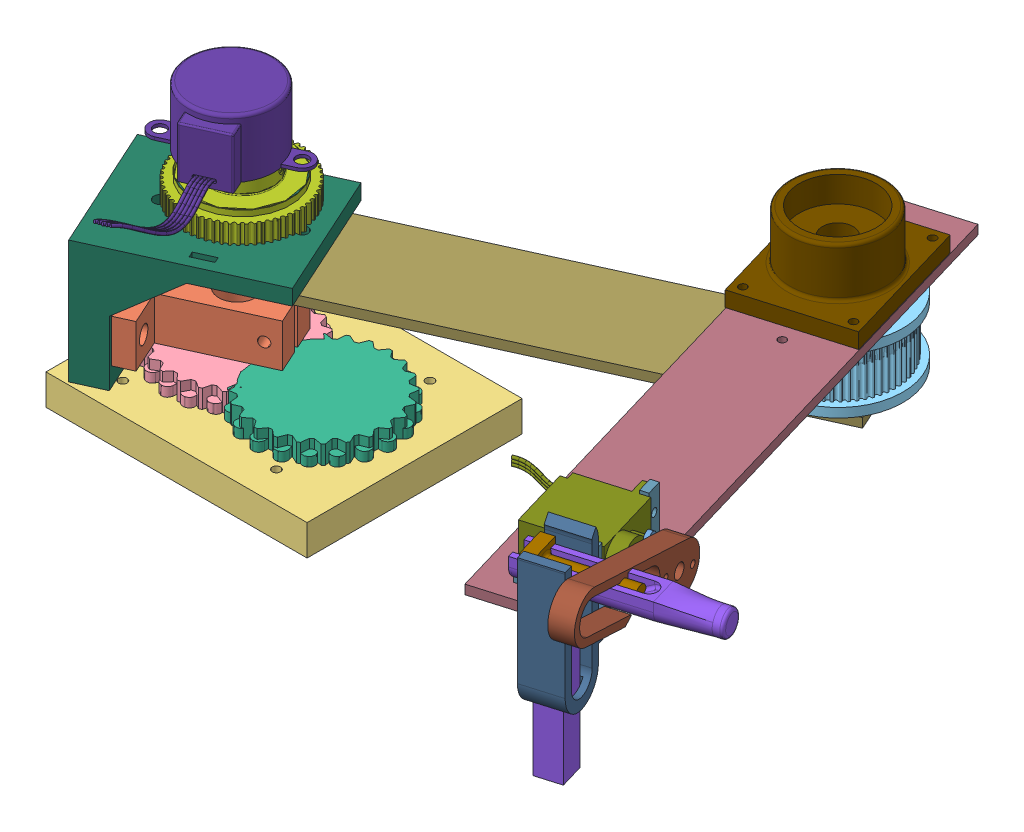
SolidWorks assembly K1-08 (mekanik), configuration Default. Lengths in mm.
Overall size (274.27 113.39 206.91).
19 component instances, 18 part files, 53 mates.
Components (placement in the parent):
- Baling-baling Servo-1: Baling-baling Servo [Peça] at (209.676 77 23.3866) x (-0.269022 -0.30223 -0.914486) z (0.085296 -0.953235 0.289945) size (34.5 3.8 16.7)
- Penjepit Shaft-1: Penjepit Shaft [SK12 SK12UU SH12A] at (17.4753 16 -35) x (0.413868 0 0.910337) z (0 1 0) size (42 37.5 14)
- Base-1: Base [Default] at (42.5 0 -35) size (85 10 70)
- Gear Besar Base-1: Gear Besar Base [Default] at (17.4753 10 -35) x (0.922569 0 0.385832) z (-0.385832 0 0.922569) size (46 6 46)
- Gear Besar Pulley-1: Gear Besar Pulley [Default] at (152.4121 67 -95.7972) x (-0.28222 0 -0.95935) z (0 -1 0) size (70 42 22)
- Gear Kecil Base-1: Gear Kecil Base [Default] at (46.1331 10 -34.3576) x (0 0 1) z (-1 0 0) size (46 6 46)
- Gear Kecil Pulley-1: Gear Kecil Pulley [Default] at (13.2127 47 -40.7516) x (-0.910337 0 0.413868) z (0 1 0) size (37.7 37.7 23)
- pin slot-1: pin slot [Default] at (217.4737 85.4111 47.4126) x (0.28222 0 0.95935) z (-0.95935 0 0.28222) size (9.53 61.3 56)
- silinder tempat spidol-1: silinder tempat spidol [Default] at (228.0265 88.1611 44.3082) x (0.28222 0 0.95935) z (-0.95935 0 0.28222) size (10 10 29.05)
- slot ujung vertikal-1: slot ujung vertikal [Default] at (201.0942 76.5 51.9705) x (-0.28222 0 -0.95935) z (0.95935 0 -0.28222) size (22 47.21 12.5)
- penggerak pulpen-1: penggerak pulpen [Default] at (215.3368 75.8151 17.8259) x (0.269022 0.30223 0.914486) z (-0.95935 0 0.28222) size (62.5 15 7)
- Arm 1 rev1 [FIX]-1: Arm 1 rev1 [FIX] [Default] at (79.5852 45 -62.6878) x (0.910337 0 -0.413868) z (-0.413868 0 -0.910337) size (185 3 35)
- Arm 2 [FIX]-1: Arm 2 [FIX] [Default] at (170.6144 66 -51.6392) x (-0.28222 0 -0.95935) z (0.95935 0 -0.28222) size (182.5 3 35)
- tempat servo spidol-1: tempat servo spidol [Default] at (199.7521 71 20.8336) x (0.28222 0 0.95935) z (-0.95935 0 0.28222) size (32.5 20 20.5)
- Penopang Stepper-1: Penopang Stepper [Default] at (126.9 50 -78.3415) x (-0.413868 0 -0.910337) z (-0.910337 0 0.413868) size (45 40 55)
- Servo Motor SG90 1PC.stp-1: Servo Motor SG90 1PC.stp [Default] at (178.6464 77 27.0424) x (0 -1 0) z (0.95935 0 -0.28222) size (12 33.08 46.7)
- Stepper motor  1PC.stp-1: Stepper motor  1PC.stp [Default] at (42.5 4.9724 -35) x (0 0 1) z (0 1 0) size (42 71.12 29)
- Tempat Bearing-2: Tempat Bearing [Default] at (152.2276 74 -95.7429) x (-0.28222 0 -0.95935) z (0.95935 0 -0.28222) size (44 21 35)
- Stepper motor  1PC.stp-2: Stepper motor  1PC.stp [Default] at (16.1098 69 -34.3792) x (-0.910337 0 0.413868) z (0 -1 0) size (42 71.12 29)
Mates (geometry in assembly coordinates):
- Concentric17: concentric anti-aligned: circle of Baling-baling Servo-1; circle of Servo Motor SG90 1PC.stp-1
- Coincident11: coincident anti-aligned: plane of Baling-baling Servo-1 through (206.0305 77 24.459) normal (-0.95935 0 0.28222); plane of Servo Motor SG90 1PC.stp-1 through (205.1133 77 21.3411) normal (0.95935 0 -0.28222)
- Concentric18: concentric aligned: cylinder of Arm 2 [FIX]-1 through (132.9548 59 -109.8784) axis (0 1 0) radius 1.25; cylinder of Tempat Bearing-2 through (132.9548 69 -109.8784) axis (0 1 0) radius 1.25
- Concentric19: concentric aligned: cylinder of Arm 2 [FIX]-1 through (171.5004 59 -81.6075) axis (0 1 0) radius 1.25; cylinder of Tempat Bearing-2 through (171.5004 69 -81.6075) axis (0 1 0) radius 1.25
- Coincident12: coincident anti-aligned: plane of Arm 2 [FIX]-1 through (170.6144 69 -51.6392) normal (0 1 0); plane of Tempat Bearing-2 through (152.2276 69 -95.7429) normal (0 -1 0)
- Concentric20: concentric anti-aligned: cylinder of Gear Besar Pulley-1 through (160.0321 63 -69.8948) axis (0 1 0) radius 1.375; cylinder of Arm 2 [FIX]-1 through (160.0321 69 -69.8948) axis (0 -1 0) radius 1.25
- Concentric21: concentric anti-aligned: cylinder of Gear Besar Pulley-1 through (144.7922 63 -121.6997) axis (0 1 0) radius 1.375; cylinder of Arm 2 [FIX]-1 through (144.7922 69 -121.6997) axis (0 -1 0) radius 1.25
- Coincident13: coincident anti-aligned: plane of Gear Besar Pulley-1 through (152.4121 66 -95.7972) normal (0 1 0); plane of Arm 2 [FIX]-1 through (170.6144 66 -51.6392) normal (0 -1 0)
- Concentric22: concentric anti-aligned: cylinder of Arm 2 [FIX]-1 through (187.7171 69 10.0414) axis (0 -1 0) radius 1.25; cylinder of tempat servo spidol-1 through (187.7171 64 10.0414) axis (0 1 0) radius 1.25
- Concentric23: concentric anti-aligned: cylinder of Arm 2 [FIX]-1 through (188.7627 69 38.399) axis (0 -1 0) radius 1.25; cylinder of tempat servo spidol-1 through (188.7627 64 38.399) axis (0 1 0) radius 1.25
- Coincident14: coincident anti-aligned: plane of Arm 2 [FIX]-1 through (170.6144 69 -51.6392) normal (0 1 0); plane of tempat servo spidol-1 through (180.0854 69 26.6191) normal (0 -1 0)
- Concentric24: concentric anti-aligned: circle of tempat servo spidol-1; circle of Servo Motor SG90 1PC.stp-1
- Concentric25: concentric aligned: circle of tempat servo spidol-1; circle of Servo Motor SG90 1PC.stp-1
- Coincident17: coincident anti-aligned: plane of tempat servo spidol-1 through (197.3537 71 21.5391) normal (-0.95935 0 0.28222); plane of Servo Motor SG90 1PC.stp-1 through (197.3537 77 21.5391) normal (0.95935 0 -0.28222)
- Concentric26: concentric aligned: cylinder of pin slot-1 through (215.1738 88.1611 43.1379) axis (0.28222 0 0.95935) radius 1.25; cylinder of silinder tempat spidol-1 through (215.1032 88.1611 42.8981) axis (0.28222 0 0.95935) radius 1.25
- Concentric27: concentric: circle of pin slot-1; circle of silinder tempat spidol-1
- Concentric28: concentric anti-aligned: cylinder of slot ujung vertikal-1 through (200.8678 50.5 40.571) axis (0 1 0) radius 1.25; cylinder of Arm 2 [FIX]-1 through (200.8678 69 40.571) axis (0 -1 0) radius 1.25
- Concentric29: concentric anti-aligned: cylinder of slot ujung vertikal-1 through (207.1036 50.5 38.7366) axis (0 1 0) radius 1.25; cylinder of Arm 2 [FIX]-1 through (207.1036 69 38.7366) axis (0 -1 0) radius 1.25
- Coincident19: coincident anti-aligned: plane of slot ujung vertikal-1 through (209.1349 69 35.0119) normal (0 -1 0); plane of Arm 2 [FIX]-1 through (170.6144 69 -51.6392) normal (0 1 0)
- Coincident20: coincident anti-aligned: plane of pin slot-1 through (203.0834 30.9111 51.6459) normal (-0.95935 0 0.28222); plane of slot ujung vertikal-1 through (204.2123 50.5 55.4833) normal (0.95935 0 -0.28222)
- Coincident21: coincident anti-aligned: plane of pin slot-1 through (218.6025 30.9111 51.25) normal (0.28222 0 0.95935); plane of slot ujung vertikal-1 through (204.2123 50.5 55.4833) normal (-0.28222 0 -0.95935)
- Concentric48: concentric aligned: cylinder of Base-1 through (42.5 10 -17.5) axis (0 -1 0) radius 2; cylinder of Stepper motor  1PC.stp-1 through (42.5 17.9724 -17.5) axis (0 -1 0) radius 2
- Concentric49: concentric aligned: cylinder of Base-1 through (42.5 10 -52.5) axis (0 -1 0) radius 1.875; cylinder of Stepper motor  1PC.stp-1 through (42.5 17.9724 -52.5) axis (0 -1 0) radius 2
- Coincident24: coincident anti-aligned: plane of Gear Kecil Base-1 through (51 16 -37.5) normal (-1 0 0); plane of Stepper motor  1PC.stp-1 through (51 8.9724 -38.6) normal (1 0 0)
- Tangent1: tangent anti-aligned: plane of Gear Kecil Base-1 through (51 16 -32.5) normal (0 0 -1); cylinder of Stepper motor  1PC.stp-1 through (49.5 14.9724 -35) axis (0 -1 0) radius 2.5
- Tangent2: tangent anti-aligned: plane of Gear Kecil Base-1 through (51 16 -37.5) normal (0 0 1); cylinder of Stepper motor  1PC.stp-1 through (49.5 14.9724 -35) axis (0 -1 0) radius 2.5
- Coincident25: coincident anti-aligned: plane of Base-1 through (42.5 10 -35) normal (0 1 0); plane of Gear Kecil Base-1 through (49.5 10 -35) normal (0 -1 0)
- Concentric50: concentric anti-aligned: cylinder of Base-1 through (17.4753 10 -35) axis (0 -1 0) radius 4.125; cylinder of Gear Besar Base-1 through (17.4753 6 -35) axis (0 1 0) radius 4.125
- Coincident26: coincident anti-aligned: plane of Base-1 through (42.5 10 -35) normal (0 1 0); plane of Gear Besar Base-1 through (17.4753 10 -35) normal (0 -1 0)
- GearMate2: gear = 20 : 40 mm: cylinder of Gear Besar Base-1 through (17.4753 16 -35) axis (0 -1 0) radius 20; cylinder of Gear Kecil Base-1 through (49.5 16 -35) axis (0 -1 0) radius 10
- Concentric51: concentric aligned: circle of Base-1; circle of Gear Kecil Base-1
- Concentric52: concentric anti-aligned: circle of Penjepit Shaft-1; circle of Gear Besar Base-1
- Concentric53: concentric aligned: cylinder of Penopang Stepper-1 through (44.1246 23 -29.5397) axis (-0.910337 0 0.413868) radius 2.375; cylinder of Penjepit Shaft-1 through (3.1594 23 -10.9157) axis (-0.910337 0 0.413868) radius 2.75
- Concentric54: concentric aligned: cylinder of Penjepit Shaft-1 through (-10.0843 23 -40.0464) axis (-0.910337 0 0.413868) radius 2.75; cylinder of Penopang Stepper-1 through (30.8809 23 -58.6705) axis (-0.910337 0 0.413868) radius 2.375
- Coincident28: coincident anti-aligned: plane of Penjepit Shaft-1 through (-12.1537 30 -44.5981) normal (-0.910337 0 0.413868); plane of Penopang Stepper-1 through (-1.0488 10 -20.172) normal (0.910337 0 -0.413868)
- Coincident29: coincident anti-aligned: plane of Penjepit Shaft-1 through (17.4753 16 -35) normal (0 -1 0); plane of Gear Besar Base-1 through (17.4753 16 -35) normal (0 1 0)
- Concentric64: concentric aligned: cylinder of Stepper motor  1PC.stp-2 through (32.0407 56 -41.6219) axis (0 1 0) radius 2; cylinder of Penopang Stepper-1 through (32.0407 45 -41.6219) axis (0 1 0) radius 1.875
- Concentric65: concentric aligned: cylinder of Penopang Stepper-1 through (0.1789 45 -27.1365) axis (0 1 0) radius 2; cylinder of Stepper motor  1PC.stp-2 through (0.1789 56 -27.1365) axis (0 1 0) radius 2
- Concentric66: concentric aligned: cylinder of Gear Besar Pulley-1 through (152.4121 48 -95.7972) axis (0 1 0) radius 4.125; cylinder of Arm 1 rev1 [FIX]-1 through (152.4121 42 -95.7972) axis (0 1 0) radius 4.125
- Concentric69: concentric anti-aligned: cylinder of Arm 1 rev1 [FIX]-1 through (0.1789 45 -27.1365) axis (0 -1 0) radius 2; cylinder of Penopang Stepper-1 through (0.1789 45 -27.1365) axis (0 1 0) radius 2
- Concentric70: concentric anti-aligned: cylinder of Arm 1 rev1 [FIX]-1 through (32.0407 45 -41.6219) axis (0 -1 0) radius 2; cylinder of Penopang Stepper-1 through (32.0407 45 -41.6219) axis (0 1 0) radius 1.875
- Coincident31: coincident anti-aligned: plane of Arm 1 rev1 [FIX]-1 through (79.5852 45 -62.6878) normal (0 1 0); plane of Penopang Stepper-1 through (126.9 45 -78.3415) normal (0 -1 0)
- Coincident32: coincident anti-aligned: plane of Gear Besar Pulley-1 through (152.4121 45 -95.7972) normal (0 -1 0); plane of Arm 1 rev1 [FIX]-1 through (79.5852 45 -62.6878) normal (0 1 0)
- Coincident34: coincident anti-aligned: plane of Baling-baling Servo-1 through (209.676 77 23.3866) normal (0.95935 0 -0.28222); plane of penggerak pulpen-1 through (208.6214 75.8151 19.8015) normal (-0.95935 0 0.28222)
- Concentric71: concentric: cylinder of Baling-baling Servo-1 through (210.8732 78.3449 27.4561) axis (0.95935 0 -0.28222) radius 0.6; cylinder of penggerak pulpen-1 through (210.8732 78.3449 27.4561) axis (0.95935 0 -0.28222) radius 0.6
- Concentric72: concentric: cylinder of Baling-baling Servo-1 through (208.3713 75.5342 18.9513) axis (0.95935 0 -0.28222) radius 0.6; cylinder of penggerak pulpen-1 through (208.3713 75.5342 18.9513) axis (0.95935 0 -0.28222) radius 0.6
- Concentric73: concentric aligned: circle of Penopang Stepper-1; circle of Gear Kecil Pulley-1
- Coincident36: coincident anti-aligned: plane of Penopang Stepper-1 through (13.2127 49 -40.7516) normal (0 1 0); plane of Gear Kecil Pulley-1 through (13.2127 49 -40.7516) normal (0 -1 0)
- Coincident43: coincident anti-aligned: plane of Gear Kecil Pulley-1 through (16.1094 67 -40.4207) normal (-0.413868 0 -0.910337); plane of Stepper motor  1PC.stp-2 through (9.0088 65 -37.1926) normal (0.413868 0 0.910337)
- Tangent5: tangent anti-aligned: plane of Gear Kecil Pulley-1 through (14.8678 67 -43.1517) normal (-0.910337 0 0.413868); cylinder of Stepper motor  1PC.stp-2 through (13.2127 59 -40.7516) axis (0 1 0) radius 2.5
- Tangent6: tangent anti-aligned: plane of Gear Kecil Pulley-1 through (10.3161 67 -41.0824) normal (0.910337 0 -0.413868); cylinder of Stepper motor  1PC.stp-2 through (13.2127 59 -40.7516) axis (0 1 0) radius 2.5
- Coincident45: coincident anti-aligned: plane of Gear Kecil Pulley-1 through (12.7694 67 -50.1251) normal (0 1 0); plane of Stepper motor  1PC.stp-2 through (13.2127 67 -40.7516) normal (0 -1 0)
- Concentric74: concentric anti-aligned: cylinder of Arm 1 rev1 [FIX]-1 through (0.1789 45 -27.1365) axis (0 -1 0) radius 2; cylinder of Penopang Stepper-1 through (0.1789 45 -27.1365) axis (0 1 0) radius 2
